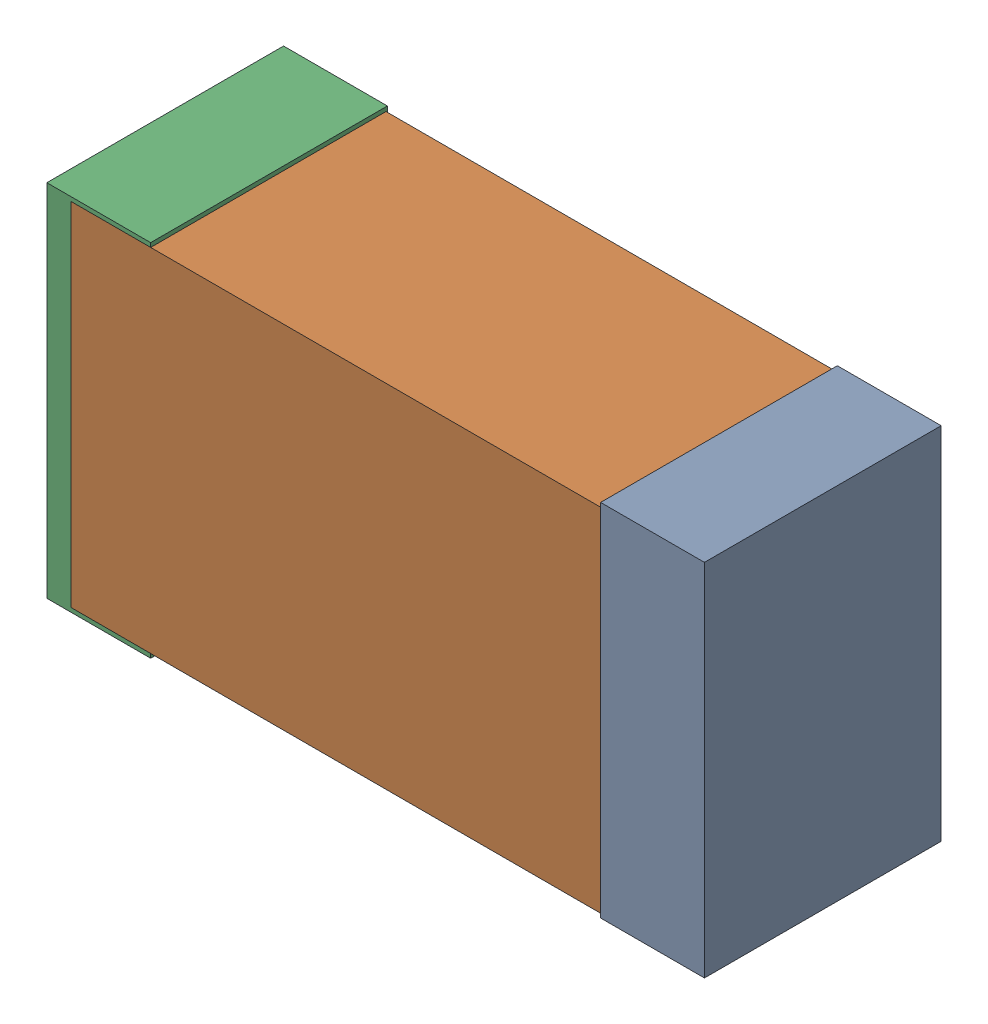
SolidWorks assembly USB67_FB2, configuration Default. Lengths in mm.
Overall size (2.38 1.3 0.85).
6 component instances, 2 part files, 0 mates.
Components (placement in the parent):
- 384311232-1: 384311232 [Default] at (152.384 86.36 -1.9574) size (0.38 1.3 0.85)
  - Extruded_8-1: Extruded_8 [Default] at origin size (0.38 1.3 0.85)
- 402662800-1: 402662800 [Default] at (151.384 86.36 -1.9524) size (2.2 1.27 0.85)
  - Extruded_30-1: Extruded_30 [Default] at origin size (2.2 1.27 0.85)
- 384311232-2: 384311232 [Default] at (150.384 86.36 -1.9574) size (0.38 1.3 0.85)
  - Extruded_8-1: Extruded_8 [Default] at origin size (0.38 1.3 0.85)
